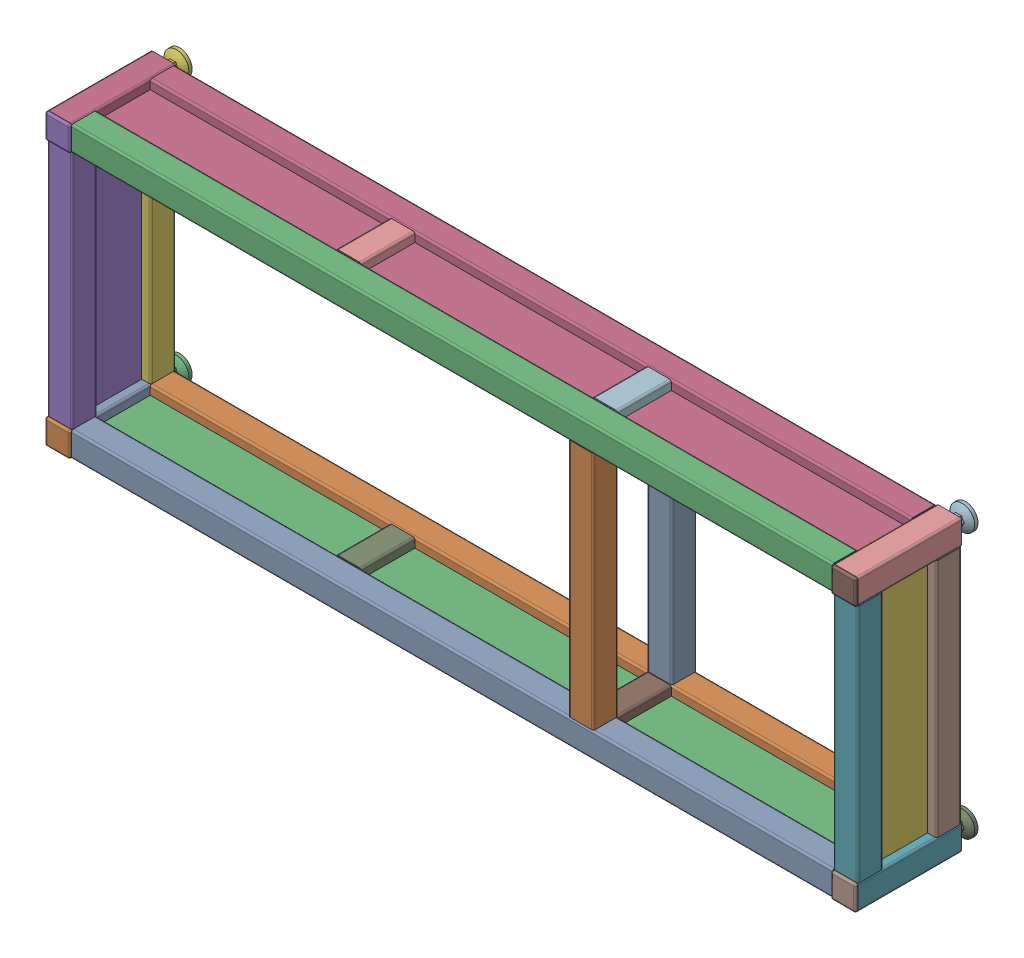
SolidWorks assembly AP_Cadre, configuration Défaut. Lengths in mm.
Overall size (980 350 148).
34 component instances, 8 part files, 15 mates.
Components (placement in the parent):
- AP_Poteau-1: AP_Poteau [Défaut] at origin size (30 30 148)
  - Rexroth30x30x125-1: Rexroth30x30x125 [Défaut] at origin size (30 30 125)
  - Rexroth-30x30_Chapeau-1: Rexroth-30x30_Chapeau [Défaut] at (0 0 125) size (30 30 3)
  - Rexroth-PiedRotul8x30-1: Rexroth-PiedRotul8x30 [Défaut] at (0 0 -20) x (1 0 0) z (0 -1 0) size (30 65 30)
- AP_Poteau-2: AP_Poteau [Défaut] at (0 320 0) size (30 30 148)
  - Rexroth30x30x125-1: Rexroth30x30x125 [Défaut] at origin size (30 30 125)
  - Rexroth-30x30_Chapeau-1: Rexroth-30x30_Chapeau [Défaut] at (0 0 125) size (30 30 3)
  - Rexroth-PiedRotul8x30-1: Rexroth-PiedRotul8x30 [Défaut] at (0 0 -20) x (1 0 0) z (0 -1 0) size (30 65 30)
- AP_Poteau-3: AP_Poteau [Défaut] at (950 0 0) size (30 30 148)
  - Rexroth30x30x125-1: Rexroth30x30x125 [Défaut] at origin size (30 30 125)
  - Rexroth-30x30_Chapeau-1: Rexroth-30x30_Chapeau [Défaut] at (0 0 125) size (30 30 3)
  - Rexroth-PiedRotul8x30-1: Rexroth-PiedRotul8x30 [Défaut] at (0 0 -20) x (1 0 0) z (0 -1 0) size (30 65 30)
- AP_Poteau-4: AP_Poteau [Défaut] at (950 320 0) size (30 30 148)
  - Rexroth30x30x125-1: Rexroth30x30x125 [Défaut] at origin size (30 30 125)
  - Rexroth-30x30_Chapeau-1: Rexroth-30x30_Chapeau [Défaut] at (0 0 125) size (30 30 3)
  - Rexroth-PiedRotul8x30-1: Rexroth-PiedRotul8x30 [Défaut] at (0 0 -20) x (1 0 0) z (0 -1 0) size (30 65 30)
- Rexroth30x30x920-1: Rexroth30x30x920 [Défaut] at (935 0 110.75) x (0 0 1) z (-1 0 0) size (30 30 920)
- Rexroth30x30x920-2: Rexroth30x30x920 [Défaut] at (935 0 15.75) x (0 0 1) z (-1 0 0) size (30 30 920)
- Rexroth30x30x920-3: Rexroth30x30x920 [Défaut] at (935 320 110.75) x (0 0 1) z (-1 0 0) size (30 30 920)
- Rexroth30x30x920-4: Rexroth30x30x920 [Défaut] at (935 320 15.75) x (0 0 1) z (-1 0 0) size (30 30 920)
- Rexroth30x30x290-1: Rexroth30x30x290 [Défaut] at (0 305 110) x (1 0 0) z (0 -1 0) size (30 30 290)
- Rexroth30x30x290-2: Rexroth30x30x290 [Défaut] at (0 305 15) x (1 0 0) z (0 -1 0) size (30 30 290)
- Rexroth30x30x290-3: Rexroth30x30x290 [Défaut] at (950 305 110) x (1 0 0) z (0 -1 0) size (30 30 290)
- Rexroth30x30x290-4: Rexroth30x30x290 [Défaut] at (950 305 15) x (1 0 0) z (0 -1 0) size (30 30 290)
- Rexroth30x30x065-1: Rexroth30x30x065 [Défaut] at (320 0 30.75) size (30 30 65)
- Rexroth30x30x065-2: Rexroth30x30x065 [Défaut] at (320 320 30.75) size (30 30 65)
- Rexroth30x30x065-3: Rexroth30x30x065 [Défaut] at (630 0 30.75) size (30 30 65)
- Rexroth30x30x065-4: Rexroth30x30x065 [Défaut] at (630 320 30.75) size (30 30 65)
- Rexroth30x30x290-5: Rexroth30x30x290 [Défaut] at (630 305 15) x (1 0 0) z (0 -1 0) size (30 30 290)
- Rexroth30x30x290-6: Rexroth30x30x290 [Défaut] at (630 305 110) x (1 0 0) z (0 -1 0) size (30 30 290)
- Bati_PlaqueFront-1: Bati_PlaqueFront [Défaut] at (6 -4 21.75) x (1 0 0) z (0 -1 0) size (938 83 8)
- Bati_PlaqueFront-2: Bati_PlaqueFront [Défaut] at (6 316 21.75) x (1 0 0) z (0 -1 0) size (938 83 8)
- Bati_PlaqueLat-1: Bati_PlaqueLat [Défaut] at (-4 6 104) x (0 1 0) z (-1 0 0) size (308 83 8)
- Bati_PlaqueLat-2: Bati_PlaqueLat [Défaut] at (946 6 104) x (0 1 0) z (-1 0 0) size (308 83 8)
Mates (geometry in assembly coordinates):
- Coïncidente1: coincident anti-aligned: plane of AP_Poteau-1/Rexroth30x30x125-1 through (15 12.75 125) normal (1 0 0); plane of Rexroth30x30x920-1 through (15 12.75 123.5) normal (-1 0 0)
- Coïncidente2: coincident aligned: plane of AP_Poteau-1/Rexroth30x30x125-1 through (-12.75 -15 125) normal (0 -1 0); plane of Rexroth30x30x920-1 through (15 -15 98) normal (0 -1 0)
- Coïncidente3: coincident: line of AP_Poteau-1/Rexroth-30x30_Chapeau-1 through (15 12.75 125.75) axis (0 -1 0); plane of Rexroth30x30x920-1 through (15 12.75 125.75) normal (0 0 1)
- Coïncidente4: coincident anti-aligned: plane of AP_Poteau-1/Rexroth30x30x125-1 through (-12.75 15 125) normal (0 1 0); plane of Rexroth30x30x290-1 through (12.75 15 122.75) normal (0 -1 0)
- Coïncidente5: coincident aligned: plane of AP_Poteau-1/Rexroth30x30x125-1 through (-15 12.75 125) normal (-1 0 0); plane of Rexroth30x30x290-1 through (-15 15 122.75) normal (-1 0 0)
- Coïncidente6: coincident: line of AP_Poteau-1/Rexroth30x30x125-1 through (12.75 15 125) axis (-1 0 0); plane of Rexroth30x30x290-1 through (-12.75 15 125) normal (0 0 1)
- Coïncidente7: coincident aligned: plane of Rexroth30x30x920-1 through (15 15 98) normal (0 1 0); plane of Rexroth30x30x065-1 through (307.25 15 95.75) normal (0 1 0)
- Coïncidente8: coincident: plane of Rexroth30x30x920-2 through (15 12.75 30.75) normal (0 0 1); line of Rexroth30x30x065-1 through (332.75 15 30.75) axis (-1 0 0)
- Distance1: distance = 320 mm aligned: plane of AP_Poteau-1/Rexroth30x30x125-1 through (15 12.75 125) normal (1 0 0); plane of Rexroth30x30x065-1 through (335 12.75 95.75) normal (1 0 0)
- Distance2: distance = 11 mm aligned: plane of Rexroth30x30x920-2 through (15 -15 3) normal (0 -1 0); plane of Bati_PlaqueFront-1 through (6 -4 104.75) normal (0 -1 0)
- Distance3: distance = 9 mm: plane of Rexroth30x30x920-1 through (15 12.75 95.75) normal (0 0 -1); line of Bati_PlaqueFront-1 through (944 -4 104.75) axis (-1 0 0)
- Distance4: distance = 9 mm: plane of AP_Poteau-3/Rexroth30x30x125-1 through (935 12.75 125) normal (-1 0 0); line of Bati_PlaqueFront-1 through (944 -4 21.75) axis (0 0 1)
- Distance5: distance = 11 mm aligned: plane of Rexroth30x30x290-1 through (-15 15 122.75) normal (-1 0 0); plane of Bati_PlaqueLat-1 through (-4 6 21) normal (-1 0 0)
- Distance6: distance = 9 mm: plane of Rexroth30x30x290-2 through (-12.75 15 30) normal (0 0 1); line of Bati_PlaqueLat-1 through (-4 314 21) axis (0 -1 0)
- Distance7: distance = 9 mm: plane of AP_Poteau-2/Rexroth30x30x125-1 through (-12.75 305 125) normal (0 -1 0); line of Bati_PlaqueLat-1 through (-4 314 104) axis (0 0 -1)
